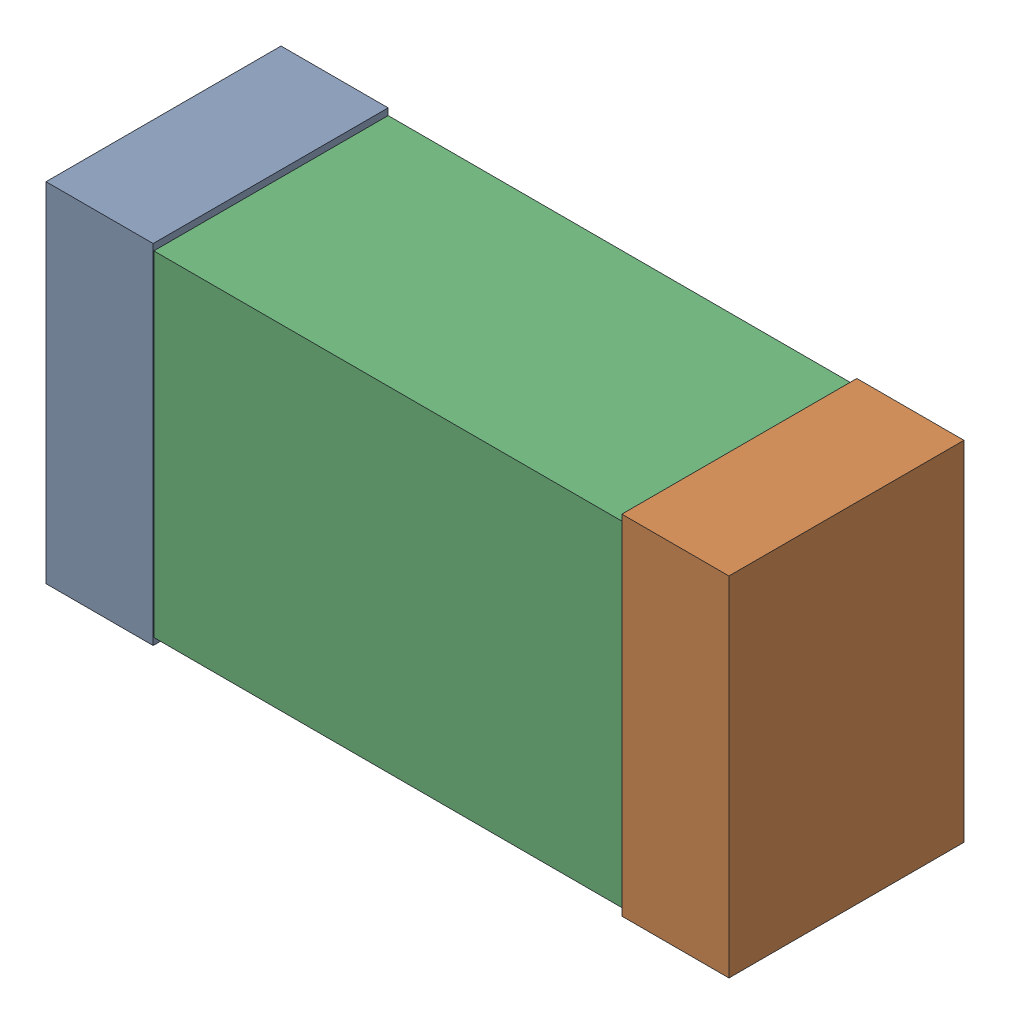
SolidWorks assembly C20, configuration Default. Lengths in mm.
Overall size (1.02 0.52 0.35).
6 component instances, 2 part files, 0 mates.
Components (placement in the parent):
- 870940480-1: 870940480 [Default] at (3.634 9.271 0) size (0.16 0.52 0.35)
  - Extruded-1: Extruded [Default] at origin size (0.16 0.52 0.35)
- 870940480-2: 870940480 [Default] at (4.494 9.271 0) size (0.16 0.52 0.35)
  - Extruded-1: Extruded [Default] at origin size (0.16 0.52 0.35)
- 870940640-1: 870940640 [Default] at (4.064 9.271 0) size (1 0.5 0.35)
  - Extruded_2-1: Extruded_2 [Default] at origin size (1 0.5 0.35)
